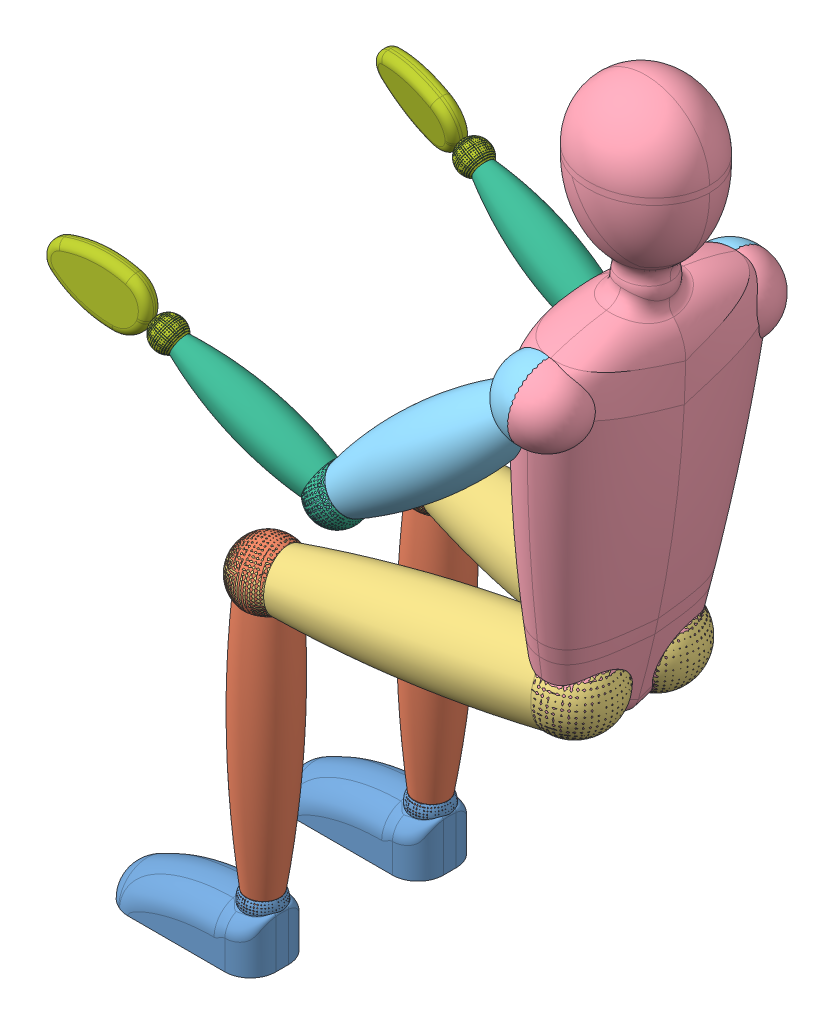
SolidWorks assembly MANNEQUIN, configuration Assis. Lengths in mm.
Overall size (756.62 1302.73 616.24).
16 component instances, 7 part files, 13 mates.
Components (placement in the parent):
- PIED^MANNEQUIN-1: PIED^MANNEQUIN [Défaut] at origin size (228.26 107.23 152.51) (virtual)
- TIBIA^MANNEQUIN-2: TIBIA^MANNEQUIN [Défaut] at (28.4477 487.474 -3.948) x (-0.028546 -0.99955 0.009234) z (-0.173325 0.014047 0.984764) size (503.5 95 95) (virtual)
- CUISSE^MANNEQUIN-1: CUISSE^MANNEQUIN [Défaut] at (417.2299 507.1547 64.1996) x (-0.983761 -0.049799 -0.172438) z (-0.173325 0.014047 0.984764) size (503.5 121.72 121.72) (virtual)
- HAUT DU CORPS^MANNEQUIN-1: HAUT DU CORPS^MANNEQUIN [Défaut] at (450 67.0554 125) x (-1 0 0) z (0 0 -1) size (756.62 841.14 616.24) (virtual)
  - BUSTE^HAUT DU CORPS_MANNEQUIN-1: BUSTE^HAUT DU CORPS_MANNEQUIN [Standard] at origin size (232.41 841.14 391.79) (virtual)
  - MEMBRE SUP.^HAUT DU CORPS_MANNEQUIN-1: MEMBRE SUP.^HAUT DU CORPS_MANNEQUIN [Défaut] at (0.6201 862.9125 138.8954) x (0.659462 0.751738 0) z (-0.154207 0.135278 0.978734) size (449.52 609.99 114) (virtual)
    - BRAS^MEMBRE SUP._HAUT DU CORPS_MANNEQUIN-1: BRAS^MEMBRE SUP._HAUT DU CORPS_MANNEQUIN [Défaut] at origin size (114 422.49 114) (virtual)
    - AVANT-BRAS^MEMBRE SUP._HAUT DU CORPS_MANNEQUIN-1: AVANT-BRAS^MEMBRE SUP._HAUT DU CORPS_MANNEQUIN [Défaut] at (0 -327.4853 0) x (0.906308 -0.422618 0) z (0 0 -1) size (313.93 76 76) (virtual)
    - MAIN^MEMBRE SUP._HAUT DU CORPS_MANNEQUIN-1: MAIN^MEMBRE SUP._HAUT DU CORPS_MANNEQUIN [Défaut] at (250.0817 -444.1003 0) x (0.906308 -0.422618 0) z (-0.02907 -0.062342 -0.997631) size (186.33 86.84 45.6) (virtual)
  - MEMBRE SUP.^HAUT DU CORPS_MANNEQUIN-3: MEMBRE SUP.^HAUT DU CORPS_MANNEQUIN [Défaut] at (0.6201 862.9125 -138.8954) x (0.659462 0.751738 0) z (0.154207 -0.135278 0.978734) size (449.52 609.99 114) (virtual)
    - BRAS^MEMBRE SUP._HAUT DU CORPS_MANNEQUIN-1: BRAS^MEMBRE SUP._HAUT DU CORPS_MANNEQUIN [Défaut] at origin size (114 422.49 114) (virtual)
    - AVANT-BRAS^MEMBRE SUP._HAUT DU CORPS_MANNEQUIN-1: AVANT-BRAS^MEMBRE SUP._HAUT DU CORPS_MANNEQUIN [Défaut] at (0 -327.4853 0) x (0.906308 -0.422618 0) z (0 0 -1) size (313.93 76 76) (virtual)
    - MAIN^MEMBRE SUP._HAUT DU CORPS_MANNEQUIN-1: MAIN^MEMBRE SUP._HAUT DU CORPS_MANNEQUIN [Défaut] at (250.0817 -444.1003 0) x (0.906308 -0.422618 0) z (-0.02907 -0.062342 -0.997631) size (186.33 86.84 45.6) (virtual)
- CUISSE^MANNEQUIN-3: CUISSE^MANNEQUIN [Défaut] at (417.2299 507.1547 185.8004) x (-0.983761 -0.049799 0.172438) z (0.173325 -0.014047 0.984764) size (503.5 121.72 121.72) (virtual)
- TIBIA^MANNEQUIN-4: TIBIA^MANNEQUIN [Défaut] at (28.4477 487.474 253.948) x (-0.028546 -0.99955 -0.009234) z (0.173325 -0.014047 0.984764) size (503.5 95 95) (virtual)
- PIED^MANNEQUIN-3: PIED^MANNEQUIN [Défaut] at (0 0 250.0013) size (228.26 107.23 152.51) (virtual)
Mates (geometry in assembly coordinates):
- Coaxial3: concentric: sphere of PIED^MANNEQUIN-1; sphere of TIBIA^MANNEQUIN-2
- Coaxial5: concentric: sphere of TIBIA^MANNEQUIN-2; sphere of CUISSE^MANNEQUIN-1
- Coaxial7: concentric: sphere of CUISSE^MANNEQUIN-1; sphere of HAUT DU CORPS^MANNEQUIN-1/BUSTE^HAUT DU CORPS_MANNEQUIN-1
- Parallèle2: parallel aligned: plane of CUISSE^MANNEQUIN-1 through (417.2299 507.1547 64.1996) normal (-0.173325 0.014047 0.984764); plane of TIBIA^MANNEQUIN-2 through (28.4477 487.474 -3.948) normal (-0.173325 0.014047 0.984764)
- Parallèle8: parallel anti-aligned: plane of HAUT DU CORPS^MANNEQUIN-1/BUSTE^HAUT DU CORPS_MANNEQUIN-1 through (450 67.0554 125) normal (0 0 -1); plane of assembly through (0 0 0) normal (0 0 1)
- Parallèle9: parallel anti-aligned: plane of HAUT DU CORPS^MANNEQUIN-1/BUSTE^HAUT DU CORPS_MANNEQUIN-1 through (450 67.0554 125) normal (-1 0 0); plane of assembly through (0 0 0) normal (1 0 0)
- Distance2: distance = 0 mm: point of HAUT DU CORPS^MANNEQUIN-1/BUSTE^HAUT DU CORPS_MANNEQUIN-1
- Angle1: planar angle = 4.537856 rad anti-aligned: plane of TIBIA^MANNEQUIN-2; plane of assembly through (0 0 125) normal (0 0 1)
- Coïncidente6: coincident anti-aligned: plane of ? through (347.4253 94.4891 125) normal (-1 0 0); plane of assembly through (0 0 0) normal (1 0 0)
- Distance3: distance = 450 mm anti-aligned: plane of HAUT DU CORPS^MANNEQUIN-1/BUSTE^HAUT DU CORPS_MANNEQUIN-1 through (450 67.0554 125) normal (-1 0 0); plane of assembly through (0 0 0) normal (1 0 0)
- Distance4: distance = 1300 mm: plane of PIED^MANNEQUIN-1 through (-135.3001 -15.8336 -0.0006) normal (0 -1 0); point of HAUT DU CORPS^MANNEQUIN-1/BUSTE^HAUT DU CORPS_MANNEQUIN-1
- Angle5: planar angle = 2.042035 rad aligned: plane of ?; plane of assembly through (0 0 0) normal (0 1 0)
- Angle6: planar angle = 2.879793 rad aligned: plane of TIBIA^MANNEQUIN-2; plane of assembly through (0 0 0) normal (0 1 0)
